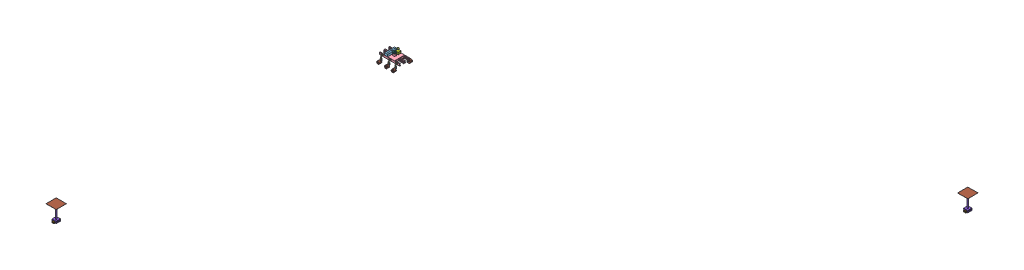
SolidWorks assembly Tets, configuration Default. Lengths in mm.
Overall size (44762.59 1974.95 46594.05).
47 component instances, 13 part files, 3 mates.
Components (placement in the parent):
- lg-1: lg [Default] at (494.3186 1187.0199 1542.4429) size (2000 1056.21 1833.55)
  - act2-1: act2 [Default] at (710 -374.097 990.1927) x (0 1 0) z (1 0 0) size (227.86 360.36 100)
  - Wheel-1: Wheel [Default] at (710 -349.0008 1023.6376) x (0 1 0) z (0 0 -1) size (274.42 270 250)
  - act1-1: act1 [Default] at (710 -171.1455 626.4214) x (-1 0 0) z (0 0 -1) size (180 401.15 176.42)
  - body-1: body [Default] at origin size (2000 400 1000)
  - act1-2: act1 [Default] at (-710 -171.1455 626.4214) x (-1 0 0) z (0 0 -1) size (180 401.15 176.42)
  - Wheel-2: Wheel [Default] at (-710 -349.0008 1023.6376) x (-1 0 0) z (0 0 -1) size (274.42 270 250)
  - act2-2: act2 [Default] at (-710 -374.097 990.1927) x (0 1 0) z (1 0 0) size (227.86 360.36 100)
  - Wheel-3: Wheel [Default] at (-710 -349.0008 -1023.6376) size (274.42 270 250)
  - act2-3: act2 [Default] at (-710 -374.097 -990.1927) x (0 1 0) z (-1 0 0) size (227.86 360.36 100)
  - act1-3: act1 [Default] at (-710 -171.1455 -626.4214) size (180 401.15 176.42)
  - act1-4: act1 [Default] at (710 -171.1455 -626.4214) size (180 401.15 176.42)
  - Wheel-4: Wheel [Default] at (710 -349.0008 -1023.6376) x (0 -1 0) z (0 0 1) size (274.42 270 250)
  - act2-4: act2 [Default] at (710 -374.097 -990.1927) x (0 1 0) z (-1 0 0) size (227.86 360.36 100)
  - tool box-1: tool box [Default] at (-340 200 0) x (0 0 1) z (-1 0 0) size (980 200 300)
  - act1-5: act1 [Default] at (50 -171.1455 626.4214) x (-1 0 0) z (0 0 -1) size (180 401.15 176.42)
  - act2-5: act2 [Default] at (50 -374.097 990.1927) x (0 1 0) z (1 0 0) size (227.86 360.36 100)
  - Wheel-5: Wheel [Default] at (50 -349.0008 1023.6376) x (-1 0 0) z (0 0 -1) size (274.42 270 250)
  - arm-1: arm [Default] at (0 400 0) x (0.719935 0 0.694042) z (-0.694042 0 0.719935) size (300 300 300)
  - Lab-1: Lab [Default] at (10 200 -340) x (0 0 1) z (-1 0 0) size (324.09 330 324.09)
  - Wheel-6: Wheel [Default] at (50 -349.0008 -1023.6376) size (274.42 270 250)
  - act1-6: act1 [Default] at (50 -171.1455 -626.4214) size (180 401.15 176.42)
  - act2-6: act2 [Default] at (50 -374.097 -990.1927) x (0 1 0) z (-1 0 0) size (227.86 360.36 100)
- pole-1: pole [Default] at (-2929.6219 552.5497 29955.8686) size (1000 1818.74 1000)
  - pilon-1: pilon [Default] at (750.6878 634.4701 2074.8363) size (400 1200 400)
  - fix-1: fix [Default] at (704.1878 324.4701 2336.3363) size (236 430 123)
    - screw - Copy-1: screw - Copy [Default] at origin size (83 330 83) (hidden)
    - Part3^fix-1: Part3^fix [Default] at origin size (236 100 123) (virtual)
    - screw2 - Copy - Copy-1: screw2 - Copy - Copy [Default] at (97.0846 0 0) size (83 330 83) (hidden)
  - fix-2: fix [Default] at (797.1878 324.4701 1813.3363) x (-1 0 0) z (0 0 -1) size (236 430 123)
    - screw - Copy-1: screw - Copy [Default] at origin size (83 330 83) (hidden)
    - Part3^fix-1: Part3^fix [Default] at origin size (236 100 123) (virtual)
    - screw2 - Copy - Copy-1: screw2 - Copy - Copy [Default] at (97.0846 0 0) size (83 330 83) (hidden)
  - pilon2-1: pilon2 [Default] at (750.6878 909.2097 2074.8363) x (-0.999521 0 0.03096) z (-0.03096 0 -0.999521) size (110 1000 110)
  - cap-2: cap [Default] at (750.6878 1909.2097 2074.8363) size (1000 264 1000)
- pole-3: pole [Default] at (40792.4098 552.5497 -15618.2053) x (0.999875 0 -0.015811) z (0.015811 0 0.999875) size (1000 1818.74 1000)
  - pilon-1: pilon [Default] at (750.6878 634.4701 2074.8363) size (400 1200 400)
  - fix-1: fix [Default] at (704.1878 324.4701 2336.3363) size (236 430 123)
    - screw - Copy-1: screw - Copy [Default] at origin size (83 330 83) (hidden)
    - Part3^fix-1: Part3^fix [Default] at origin size (236 100 123) (virtual)
    - screw2 - Copy - Copy-1: screw2 - Copy - Copy [Default] at (97.0846 0 0) size (83 330 83) (hidden)
  - fix-2: fix [Default] at (797.1878 324.4701 1813.3363) x (-1 0 0) z (0 0 -1) size (236 430 123)
    - screw - Copy-1: screw - Copy [Default] at origin size (83 330 83) (hidden)
    - Part3^fix-1: Part3^fix [Default] at origin size (236 100 123) (virtual)
    - screw2 - Copy - Copy-1: screw2 - Copy - Copy [Default] at (97.0846 0 0) size (83 330 83) (hidden)
  - pilon2-1: pilon2 [Default] at (750.6878 909.2097 2074.8363) x (-0.999521 0 0.03096) z (-0.03096 0 -0.999521) size (110 1000 110)
  - cap-2: cap [Default] at (750.6878 1909.2097 2074.8363) size (1000 264 1000)
Mates (geometry in assembly coordinates):
- Coincident4: coincident: plane of lg-1/body-1 through (494.3186 1187.0199 1542.4429) normal (0 -1 0); plane of pole-3/pilon-1 through (41575.8086 1187.0199 -13555.4973) normal (0 -1 0)
- Coincident5: coincident: plane of lg-1/body-1 through (494.3186 1187.0199 1542.4429) normal (0 -1 0); plane of pole-1/pilon-1 through (136.5682 1187.0199 12165.1925) normal (0 -1 0)
- Distance3: distance = 30000 mm: point of pole-1/pilon-1; point of lg-1/body-1
